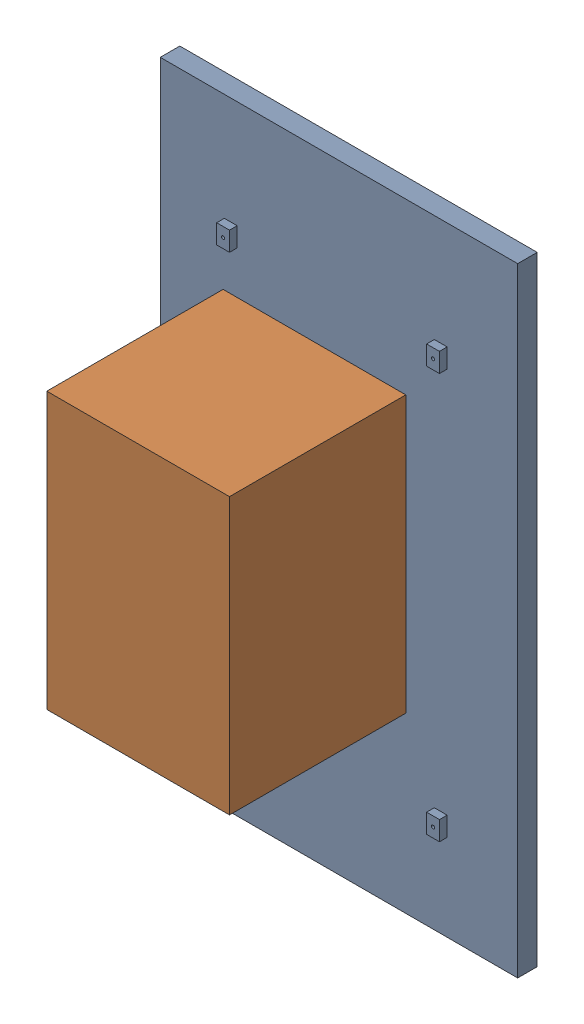
SolidWorks assembly ScreenPi, configuration Default. Lengths in mm.
Overall size (111.5 193 63.5).
2 component instances, 2 part files, 2 mates.
Components (placement in the parent):
- Screen-1: Screen [Default] at (9.8156 56.5814 211.084) size (111.5 193 8.5)
- Raspberry Pi-1: Raspberry Pi [Default] at (88.8156 199.0814 219.584) x (-1 0 0) z (0 0 1) size (57 86 55)
Mates (geometry in assembly coordinates):
- Coincident7: coincident anti-aligned: circle of Screen-1; circle of Raspberry Pi-1
- Parallel1: parallel aligned: line of Screen-1 through (79.3156 170.5814 219.584) axis (0 1 0); line of Raspberry Pi-1 through (88.8156 113.0814 219.584) axis (0 1 0)
